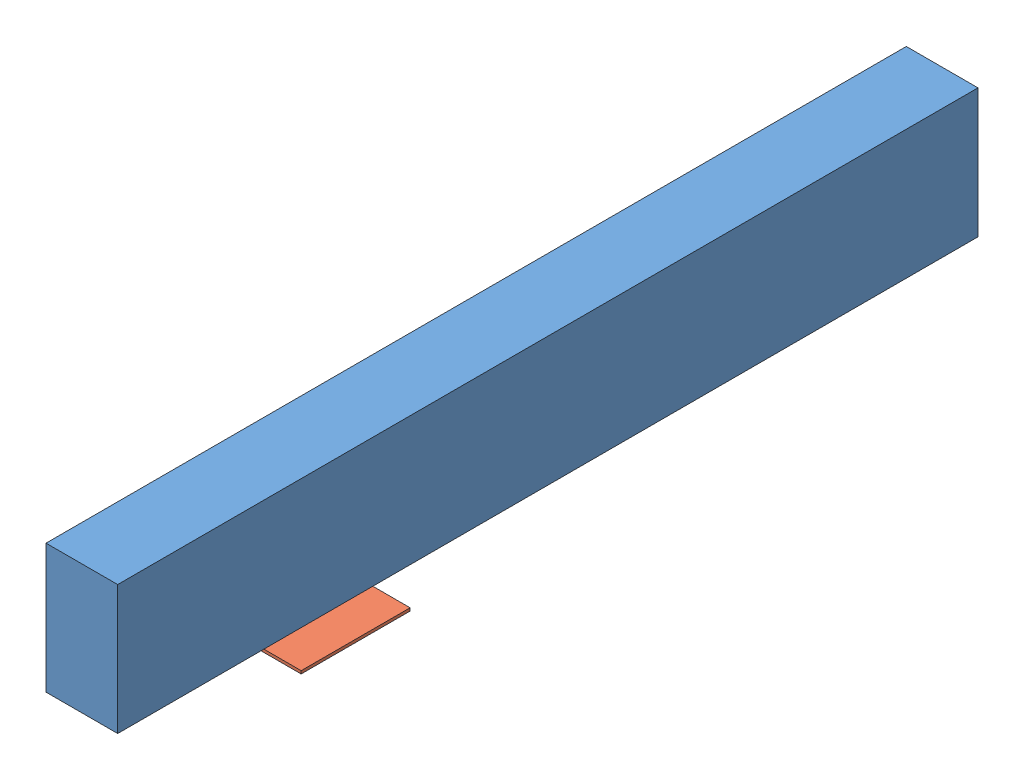
SolidWorks assembly Assemblage1, configuration Défaut. Lengths in mm.
Overall size (38 46 300).
2 component instances, 2 part files, 2 mates.
Components (placement in the parent):
- Bras-1: Bras [Défaut] at (-12.1817 -25.0781 -150) size (25 45 300)
- caméra-1: caméra [Défaut] at (-12.1817 -25.0781 61.0253) x (1 0 0) z (0 -1 0) size (38 38 1)
Mates (geometry in assembly coordinates):
- Coïncidente7: coincident: plane of Bras-1 through (-12.1817 -25.0781 150) normal (0 -1 0); plane of caméra-1 through (-11.6099 -25.0781 98.9534) normal (0 1 0)
- Coïncidente8: coincident aligned: plane of Bras-1 through (-12.1817 -25.0781 150) normal (-1 0 0); plane of caméra-1 through (-12.1817 -26.0781 61.0253) normal (-1 0 0)
